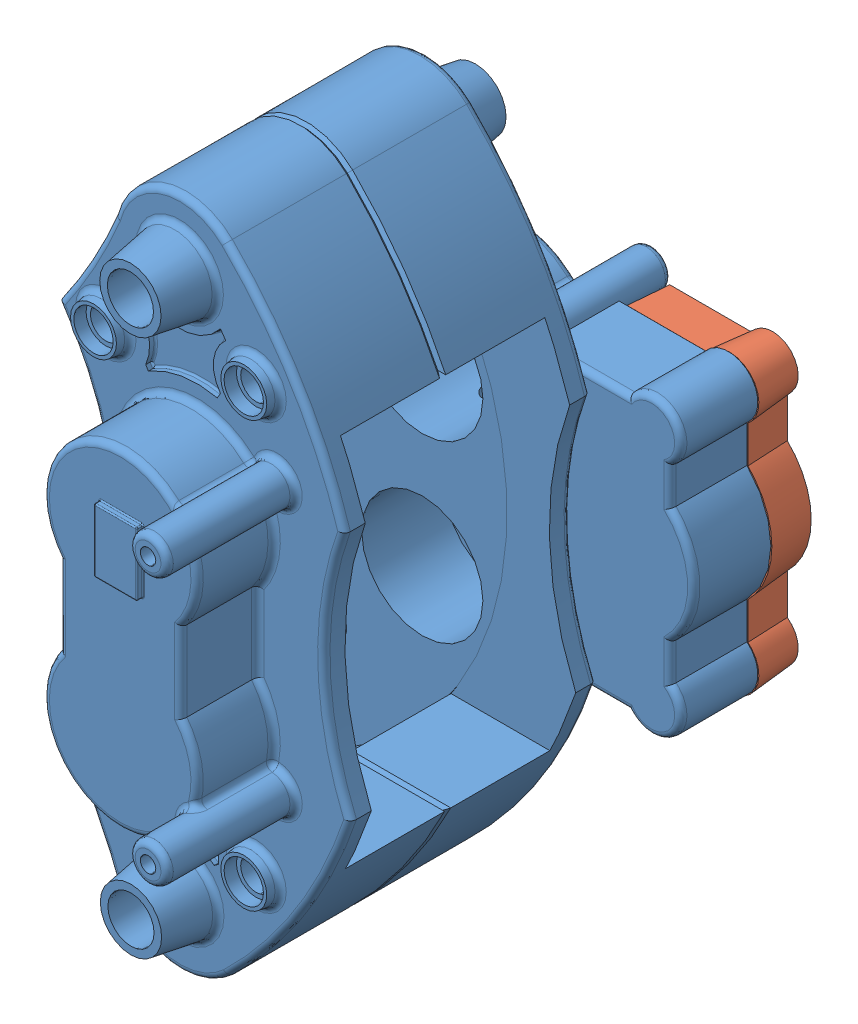
SolidWorks assembly CaliperBooster, configuration Default. Lengths in mm.
Overall size (160.83 277.42 207.96).
3 component instances, 3 part files, 0 mates.
Components (placement in the parent):
- Caliper2M-1: Caliper2M [Default] at (-129.392 15.613 57.6711) size (160.8 277.42 207.96)
- boostercover-1: boostercover [Default] at (-129.3557 15.2726 -76.0494) x (-1 0 0) z (0 0 -1) size (84.06 121.49 17.78)
- booster-1: booster [Default] at (40.1517 17.21 -111.246) x (-1 0 0) z (0 0 1) (suppressed, hidden)
